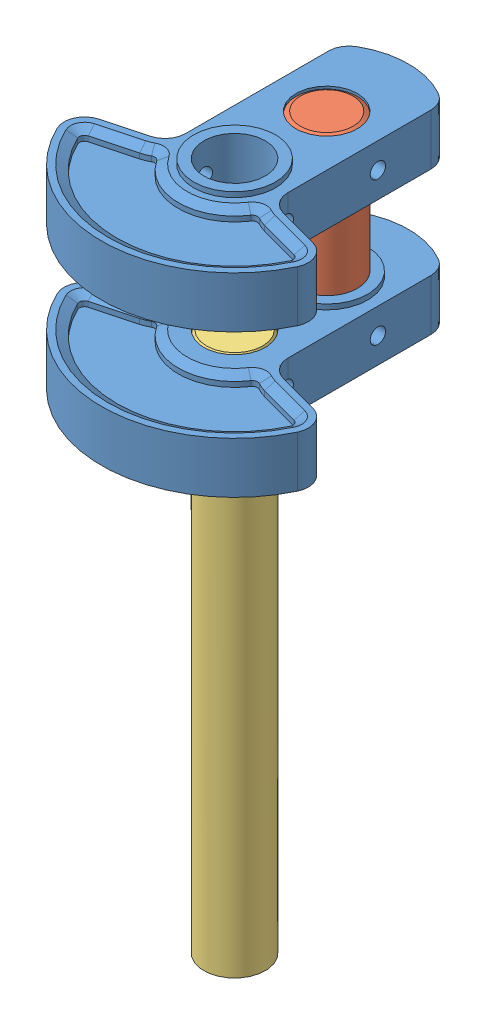
SolidWorks assembly Crankshaft Assembly, configuration Default. Lengths in mm.
Overall size (47.72 135 60).
4 component instances, 3 part files, 6 mates.
Components (placement in the parent):
- #16Counter Weight-1: #16Counter Weight [Default] at (-22.0968 36.3657 62.6264) x (-1 0 0) z (0 0 1) size (47.72 12 60)
- #18Crank Shaft Pin-1: #18Crank Shaft Pin [Default] at (-22.0968 22.3657 44.6264) x (0 0 1) z (-1 0 0) size (12 38 12)
- #16Counter Weight-2: #16Counter Weight [Default] at (-22.0968 8.3657 62.6264) size (47.72 12 60)
- #17Crank Shaft Rod-1: #17Crank Shaft Rod [Default] at (-22.0968 13.3657 62.6264) x (-1 0 0) z (0 0 1) size (12 106 12)
Mates (geometry in assembly coordinates):
- Concentric3: concentric aligned: cylinder of #18Crank Shaft Pin-1 through (-22.0968 41.3657 44.6264) axis (0 -1 0) radius 6; cylinder of #16Counter Weight-2 through (-22.0968 14.3657 44.6264) axis (0 -1 0) radius 6
- Coincident1: coincident aligned: cylinder of #18Crank Shaft Pin-1 through (-16.0968 8.3657 44.6264) axis (-1 0 0) radius 1.5; circle of #16Counter Weight-2
- Concentric5: concentric anti-aligned: cylinder of #16Counter Weight-2 through (-22.0968 14.3657 62.6264) axis (0 -1 0) radius 6; cylinder of #17Crank Shaft Rod-1 through (-22.0968 -92.6343 62.6264) axis (0 1 0) radius 6
- Concentric6: concentric anti-aligned: cylinder of #16Counter Weight-2 through (-45.9577 8.3657 62.6264) axis (1 0 0) radius 1.5; cylinder of #17Crank Shaft Rod-1 through (-12.0968 8.3657 62.6264) axis (-1 0 0) radius 1.5
- Concentric7: concentric anti-aligned: cylinder of #16Counter Weight-1 through (-22.0968 30.3657 44.6264) axis (0 1 0) radius 6; cylinder of #18Crank Shaft Pin-1 through (-22.0968 41.3657 44.6264) axis (0 -1 0) radius 6
- Concentric8: concentric aligned: cylinder of #16Counter Weight-1 through (1.7641 36.3657 44.6264) axis (-1 0 0) radius 1.5; cylinder of #18Crank Shaft Pin-1 through (-16.0968 36.3657 44.6264) axis (-1 0 0) radius 1.5
